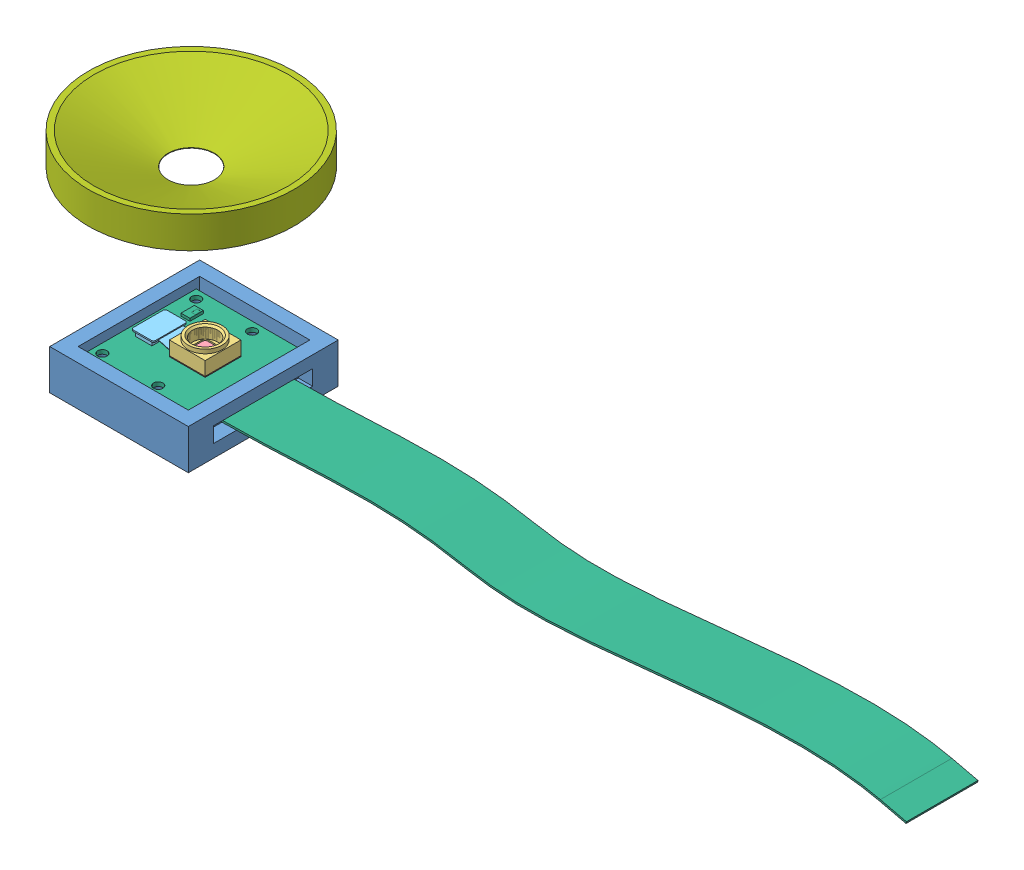
SolidWorks assembly cam case 03, configuration Default. Lengths in mm.
Overall size (190.94 49.89 45.94).
10 component instances, 8 part files, 3 mates.
Components (placement in the parent):
- Camera case-1: Camera case [Default] at (1.4614 12.9279 38.7184) size (30.99 8.96 33.53)
- RasPi_Camera-1: RasPi_Camera [FOV] at (16.2834 20.7296 25.1287) x (0 0 1) z (-1 0 0) size (119.2 128.3 208.52)
  - OVA5647-1: OVA5647 [FOV] at origin size (119.2 123.21 87.35)
    - OVA5647-1: OVA5647 [Standard] at (0.32 0 -0.175) size (8 0.68 8)
    - OVA5647_Housing-1: OVA5647_Housing [Standard] at origin size (8 3.95 8)
    - OVA5647_IR-Glas-1: OVA5647_IR-Glas [Standard] at (0 0.95 0) x (-1 0 0) z (0 0 1) size (6.3 0.35 6.3)
    - OVA5647_Lens-1: OVA5647_Lens [FOV] at (0 3.95 0) size (119.2 121.26 87.35) (hidden)
    - OVA5647_Pigtail-1: OVA5647_Pigtail [Standard] at origin size (7.6 1.3 8.75)
  - RasPi_Camera_Board-1: RasPi_Camera_Board [Standard] at (0 -0.5517 0) x (-1 0 0) z (0 0 -1) size (25 5.7 179.34)
- cam wheel-2: cam wheel [Default] at (13.1496 55.7013 25.1072) size (45.94 7.11 45.94)
Mates (geometry in assembly coordinates):
- Width1: width aligned: plane of Camera case-1 through (26.1054 12.9279 11.539) normal (0 0 1); plane of Camera case-1 through (1.4614 12.9279 38.7184) normal (0 0 -1); plane of RasPi_Camera-1/RasPi_Camera_Board-1 through (1.7834 19.2779 37.6287) normal (0 0 1); plane of RasPi_Camera-1/RasPi_Camera_Board-1 through (1.7834 19.2779 12.6287) normal (0 0 -1)
- Width2: width aligned: plane of RasPi_Camera-1/RasPi_Camera_Board-1 through (25.7834 19.2779 37.6287) normal (1 0 0); plane of RasPi_Camera-1/RasPi_Camera_Board-1 through (1.7834 19.2779 37.6287) normal (-1 0 0); plane of Camera case-1 through (1.4614 12.9279 11.539) normal (1 0 0); plane of Camera case-1 through (26.1054 12.9279 38.7184) normal (-1 0 0)
- Coincident3: coincident aligned: plane of Camera case-1 through (16.2834 19.2779 14.6287) normal (0 1 0); circle of RasPi_Camera-1/RasPi_Camera_Board-1
